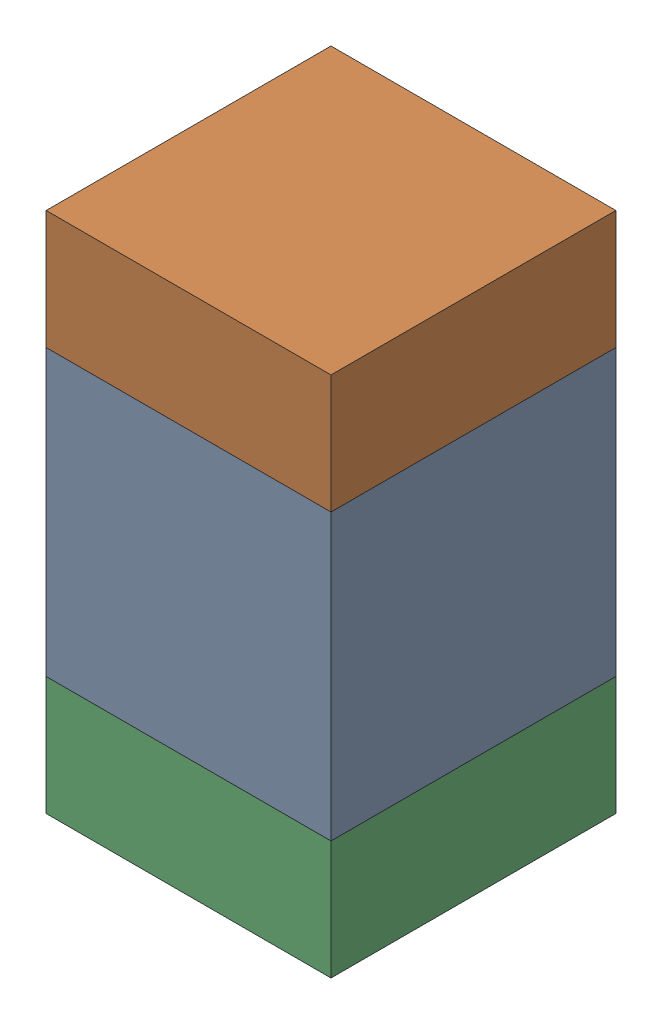
SolidWorks assembly C323_1PCB, configuration Default. Lengths in mm.
Overall size (0.6 1.1 0.6).
6 component instances, 2 part files, 0 mates.
Components (placement in the parent):
- 761606048-1: 761606048 [Default] at (140.4 119.4 -2.2638) size (0.6 0.6 0.6)
  - Extruded_9-1: Extruded_9 [Default] at origin size (0.6 0.6 0.6)
- 854785296-1: 854785296 [Default] at (140.4 119.825 -2.2638) size (0.6 0.25 0.6)
  - Extruded_10-1: Extruded_10 [Default] at origin size (0.6 0.25 0.6)
- 854785296-2: 854785296 [Default] at (140.4 118.975 -2.2638) size (0.6 0.25 0.6)
  - Extruded_10-1: Extruded_10 [Default] at origin size (0.6 0.25 0.6)
